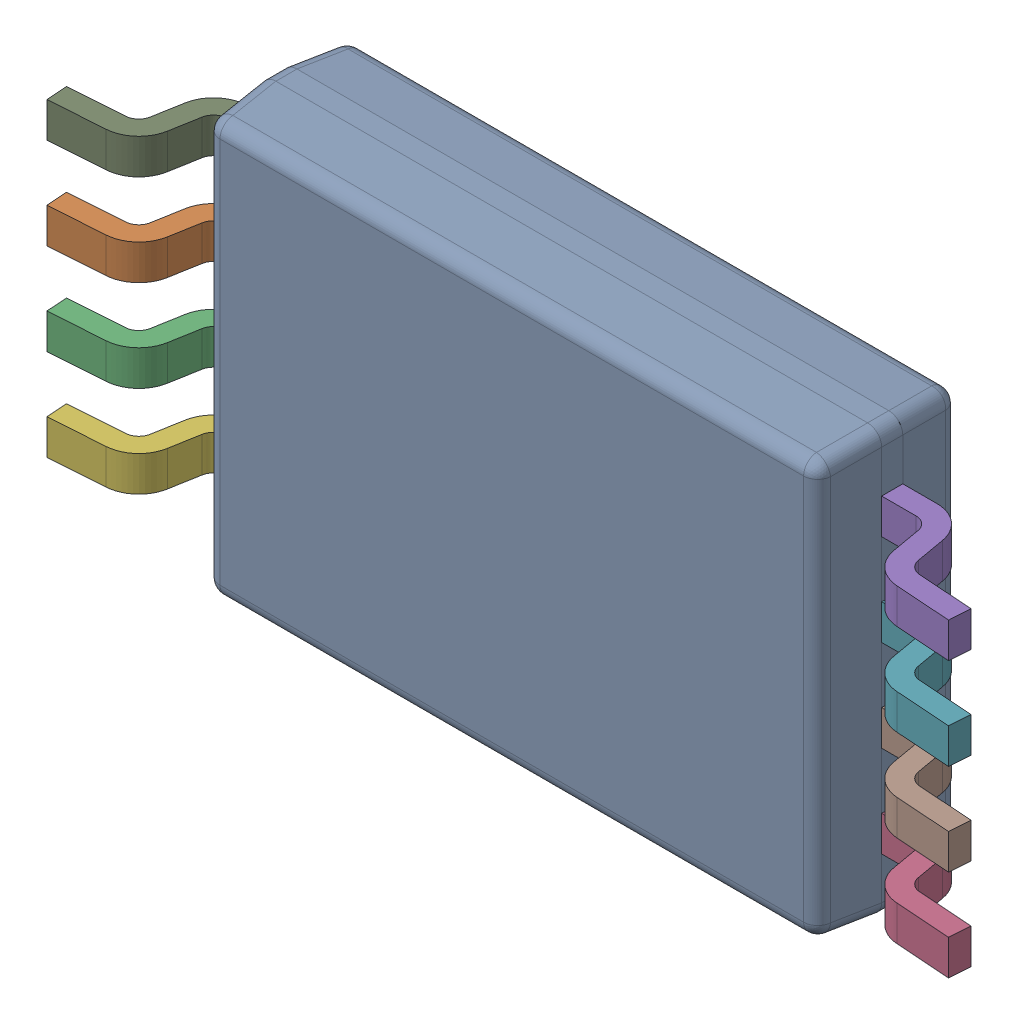
SolidWorks assembly PW0008A_ASM, configuration По умолчанию. Lengths in mm.
Overall size (6.42 3.01 1.1).
9 component instances, 2 part files, 0 mates.
Components (placement in the parent):
- PW0008A_ASM-Part-1-1: PW0008A_ASM-Part-1 [По умолчанию] at origin size (4.41 3.01 1)
- PW0008A_ASM-Part-2-1: PW0008A_ASM-Part-2 [По умолчанию] at (-2.575 0.325 -2.3511) x (0 1 0) z (-1 0 0) size (0.25 0.68 1.01)
- PW0008A_ASM-Part-2-2: PW0008A_ASM-Part-2 [По умолчанию] at (-2.575 -0.325 -2.3511) x (0 1 0) z (-1 0 0) size (0.25 0.68 1.01)
- PW0008A_ASM-Part-2-3: PW0008A_ASM-Part-2 [По умолчанию] at (2.575 -0.975 -2.3511) x (0 -1 0) z (1 0 0) size (0.25 0.68 1.01)
- PW0008A_ASM-Part-2-4: PW0008A_ASM-Part-2 [По умолчанию] at (2.575 0.975 -2.3511) x (0 -1 0) z (1 0 0) size (0.25 0.68 1.01)
- PW0008A_ASM-Part-2-5: PW0008A_ASM-Part-2 [По умолчанию] at (-2.575 -0.975 -2.3511) x (0 1 0) z (-1 0 0) size (0.25 0.68 1.01)
- PW0008A_ASM-Part-2-6: PW0008A_ASM-Part-2 [По умолчанию] at (2.575 0.325 -2.3511) x (0 -1 0) z (1 0 0) size (0.25 0.68 1.01)
- PW0008A_ASM-Part-2-7: PW0008A_ASM-Part-2 [По умолчанию] at (2.575 -0.325 -2.3511) x (0 -1 0) z (1 0 0) size (0.25 0.68 1.01)
- PW0008A_ASM-Part-2-8: PW0008A_ASM-Part-2 [По умолчанию] at (-2.575 0.975 -2.3511) x (0 1 0) z (-1 0 0) size (0.25 0.68 1.01)
